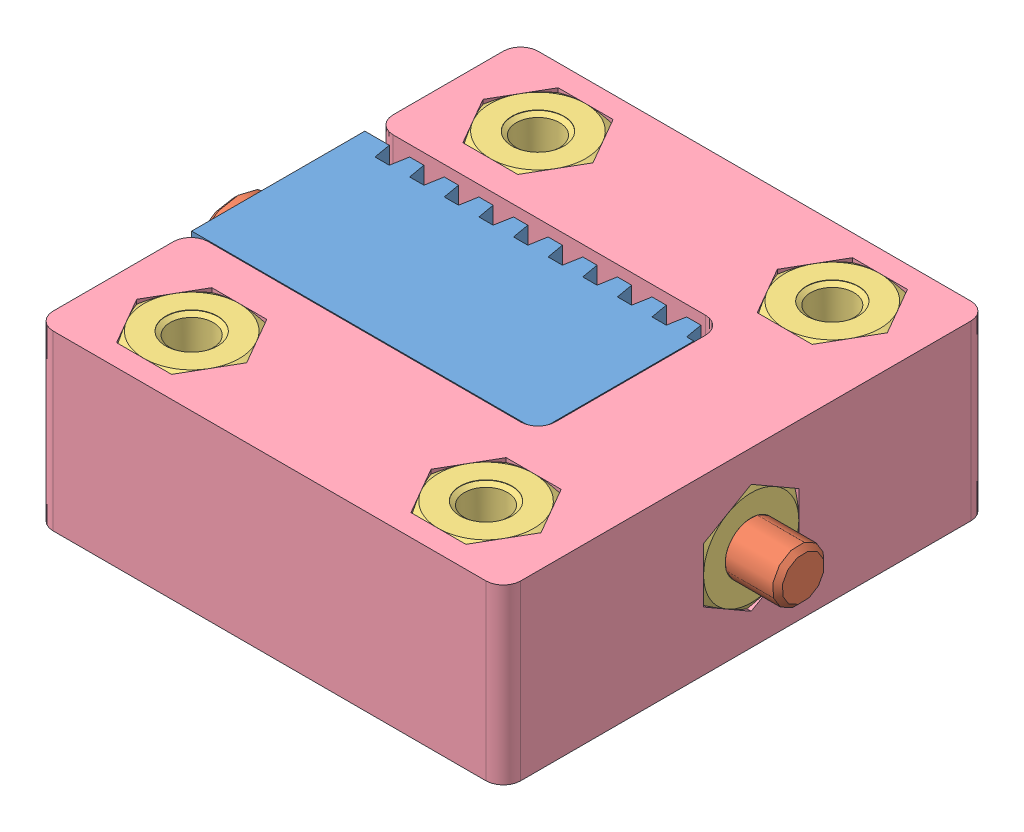
SolidWorks assembly x_y belt tensioner, configuration Default. Lengths in mm.
Overall size (33 10 28).
8 component instances, 4 part files, 21 mates.
Components (placement in the parent):
- x_y belt tensioner 1-1: x_y belt tensioner 1 [Default] at origin size (20 10 10)
- socket head cap screw_am-1: socket head cap screw_am [B18.3.1M - 3 x 0.5 x 30 Hex SHCS -- 18NHX] at (-13 5 -0.315) x (1 0 0) z (0 -0.687792 -0.725908) size (33 5.5 5.5)
- hex nut style 1_am-1: hex nut style 1_am [B18.2.4.1M - Hex nut, Style 1,  M3 x 0.5 --D-N] at (17 5 -0.315) x (0 0 -1) z (1 0 0) size (5.5 6.35 2.4)
- x_y belt tensioner 2-1: x_y belt tensioner 2 [Default] at (-10 0 14) size (27 10 28)
- hex nut style 1_am-3: hex nut style 1_am [B18.2.4.1M - Hex nut, Style 1,  M3 x 0.5 --D-N] at (-5 7.6 10) x (0 0 -1) z (0 -1 0) size (5.5 6.35 2.4)
- hex nut style 1_am-5: hex nut style 1_am [B18.2.4.1M - Hex nut, Style 1,  M3 x 0.5 --D-N] at (12 7.6 10) x (0 0 -1) z (0 -1 0) size (5.5 6.35 2.4)
- hex nut style 1_am-7: hex nut style 1_am [B18.2.4.1M - Hex nut, Style 1,  M3 x 0.5 --D-N] at (12 7.6 -10) x (0 0 -1) z (0 -1 0) size (5.5 6.35 2.4)
- hex nut style 1_am-9: hex nut style 1_am [B18.2.4.1M - Hex nut, Style 1,  M3 x 0.5 --D-N] at (-5 7.6 -10) x (0 0 -1) z (0 -1 0) size (5.5 6.35 2.4)
Mates (geometry in assembly coordinates):
- Coincident1: coordinate: point of x_y belt tensioner 1-1; point of assembly
- Parallel5: parallel anti-aligned: plane of hex nut style 1_am-1 through (17 5 -0.315) normal (0 0 -1); plane of assembly through (0 0 0) normal (0 0 1)
- Coincident5: coincident aligned: plane of x_y belt tensioner 1-1 through (-10 10 -5) normal (-1 0 0); plane of x_y belt tensioner 2-1 through (-10 10 14) normal (-1 0 0)
- Distance1: distance = 9 mm aligned: plane of x_y belt tensioner 2-1 through (-10 10 14) normal (0 0 1); plane of x_y belt tensioner 1-1 through (-10 10 5) normal (0 0 1)
- Concentric3: concentric anti-aligned: cylinder of x_y belt tensioner 2-1 through (-5 10 10) axis (0 1 0) radius 1.7; cylinder of hex nut style 1_am-3 through (-5 10 10) axis (0 -1 0) radius 1.25
- Coincident7: coincident aligned: plane of x_y belt tensioner 2-1 through (-10 10 14) normal (0 1 0); plane of hex nut style 1_am-3 through (-1.8246 10 10) normal (0 1 0)
- Parallel1: parallel aligned: plane of hex nut style 1_am-3; plane of assembly through (0 0 0) normal (1 0 0)
- Coincident8: coincident aligned: plane of x_y belt tensioner 2-1 through (-10 10 14) normal (0 1 0); plane of hex nut style 1_am-5 through (15.1754 10 10) normal (0 1 0)
- Parallel2: parallel aligned: plane of hex nut style 1_am-5; plane of assembly through (0 0 0) normal (1 0 0)
- Concentric4: concentric anti-aligned: cylinder of x_y belt tensioner 2-1 through (12 10 10) axis (0 1 0) radius 1.7; cylinder of hex nut style 1_am-5 through (12 10 10) axis (0 -1 0) radius 1.25
- Concentric5: concentric anti-aligned: cylinder of x_y belt tensioner 2-1 through (12 10 -10) axis (0 1 0) radius 1.7; cylinder of hex nut style 1_am-7 through (12 10 -10) axis (0 -1 0) radius 1.25
- Parallel3: parallel aligned: plane of hex nut style 1_am-7; plane of assembly through (0 0 0) normal (1 0 0)
- Coincident10: coincident aligned: plane of x_y belt tensioner 2-1 through (-10 10 14) normal (0 1 0); plane of hex nut style 1_am-7 through (15.1754 10 -10) normal (0 1 0)
- Concentric6: concentric anti-aligned: cylinder of x_y belt tensioner 2-1 through (-5 10 -10) axis (0 1 0) radius 1.7; cylinder of hex nut style 1_am-9 through (-5 10 -10) axis (0 -1 0) radius 1.25
- Parallel4: parallel aligned: plane of hex nut style 1_am-9; plane of assembly through (0 0 0) normal (1 0 0)
- Coincident11: coincident aligned: plane of x_y belt tensioner 2-1 through (-10 10 14) normal (0 1 0); plane of hex nut style 1_am-9 through (-1.8246 10 -10) normal (0 1 0)
- Coincident12: coincident aligned: plane of x_y belt tensioner 1-1 through (0 0 0) normal (0 -1 0); plane of x_y belt tensioner 2-1 through (-10 0 14) normal (0 -1 0)
- Concentric7: concentric anti-aligned: cylinder of socket head cap screw_am-1 through (-44.75 5 -0.315) axis (-1 0 0) radius 1.5; cylinder of x_y belt tensioner 2-1 through (17 5 -0.315) axis (1 0 0) radius 1.7
- Concentric8: concentric anti-aligned: cylinder of socket head cap screw_am-1 through (-44.75 5 -0.315) axis (-1 0 0) radius 1.5; cylinder of hex nut style 1_am-1 through (14.6 5 -0.315) axis (1 0 0) radius 1.25
- Coincident15: coincident anti-aligned: plane of x_y belt tensioner 1-1 through (-10 10 -5) normal (-1 0 0); plane of socket head cap screw_am-1 through (-10 3.0038 1.5764) normal (1 0 0)
- Coincident16: coincident aligned: plane of hex nut style 1_am-1 through (17 8.1754 -0.315) normal (1 0 0); plane of x_y belt tensioner 2-1 through (17 10 14) normal (1 0 0)
